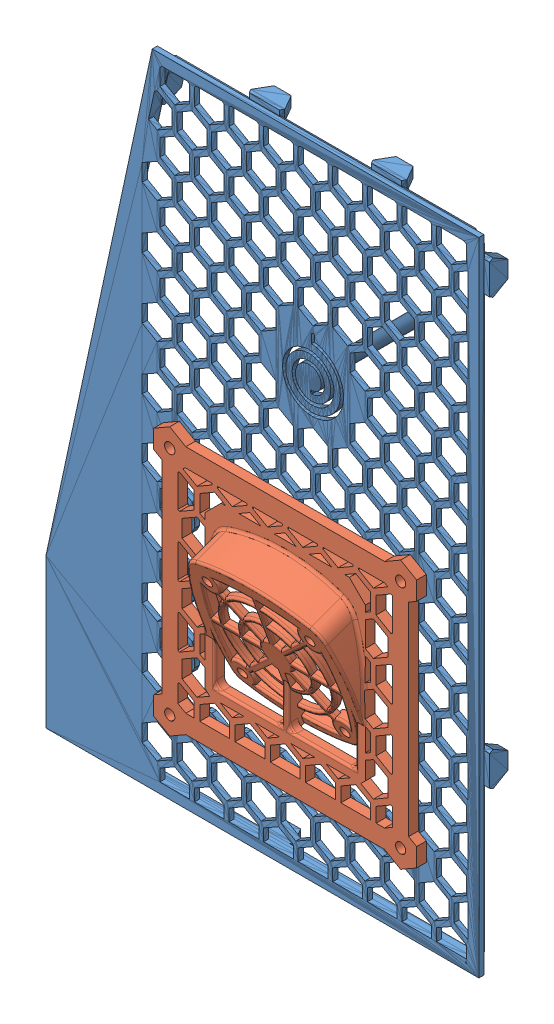
SolidWorks assembly fan cover, configuration Default. Lengths in mm.
Overall size (135 200 46.45).
2 component instances, 2 part files, 4 mates.
Components (placement in the parent):
- Another_Mainboard_Mosfet_Frame_Remix_V2-1: Another_Mainboard_Mosfet_Frame_Remix_V2 [Default] at origin size (135 200 32.4)
- Part3^fan cover-1: Part3^fan cover [Default] at (0 0 50) size (82 83.55 18.78) (virtual)
Mates (geometry in assembly coordinates):
- InPlace1: in place: plane of Another_Mainboard_Mosfet_Frame_Remix_V2-1 through (0 0 50) normal (0 0 1); plane of Part3^fan cover-1 through (0 0 50) normal (0 0 1); moOrthogonalPlaneRef_w of Another_Mainboard_Mosfet_Frame_Remix_V2-1 through (0 0 50) normal (0 0 1); plane of Part3^fan cover-1 through (0 0 50) normal (0 1 0); plane of Another_Mainboard_Mosfet_Frame_Remix_V2-1 through (0 0 50) normal (0 0 1); plane of Part3^fan cover-1 through (0 0 50) normal (1 0 0); plane of Another_Mainboard_Mosfet_Frame_Remix_V2-1 through (0 0 50) normal (0 0 1); unknown of Part3^fan cover-1
- Coincident1: coincident aligned: plane of ?; plane of ?
- Coincident2: coincident aligned: moOrthogonalPlaneRef_w of Another_Mainboard_Mosfet_Frame_Remix_V2-1 through (0 0 50) normal (0 1 0); plane of Part3^Assem1-1 through (0 0 50) normal (0 1 0)
- Coincident3: coincident anti-aligned: moOrthogonalPlaneRef_w of Another_Mainboard_Mosfet_Frame_Remix_V2-1 through (0 0 50) normal (-1 0 0); plane of Part3^Assem1-1 through (0 0 50) normal (1 0 0)
